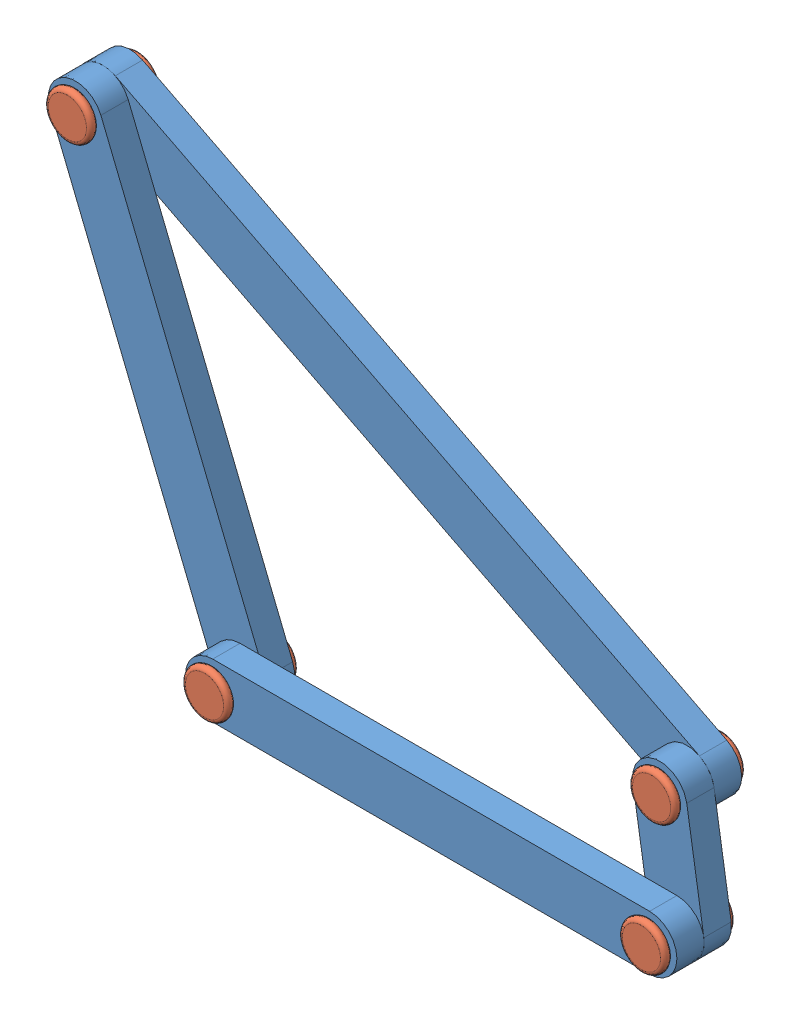
SolidWorks assembly four_bar_linkage, configuration Default. Lengths in mm.
Overall size (155.65 110.94 22.86).
8 component instances, 2 part files, 15 mates.
Components (placement in the parent):
- link-1: link [4] at (-72.1431 -68.9681 0) size (114.3 12.7 6.35)
- link_coupler-1: link_coupler [Default] at (-72.1431 -68.9681 -3.175) x (0 0 -1) z (0.970878 0.239573 0) size (16.51 10.79 10.79)
- link_coupler-2: link_coupler [Default] at (-173.7431 -68.9681 -3.175) x (0 0 -1) z (0.119211 -0.992869 0) size (16.51 10.79 10.79)
- link-2: link [4] at (-211.9868 25.1594 -6.35) x (-0.376415 0.926451 0) z (0 0 -1) size (114.3 12.7 6.35)
- link-3: link [1] at (-76.1226 -43.8817 -6.35) x (-0.156675 0.98765 0) z (0 0 1) size (38.1 12.7 6.35)
- link_coupler-3: link_coupler [Default] at (-211.9868 25.1594 -9.525) x (0 0 -1) z (0.614326 0.789053 0) size (16.51 10.79 10.79)
- link_coupler-4: link_coupler [Default] at (-76.1226 -43.8817 -9.525) x (0 0 -1) z (-0.985541 -0.16944 0) size (16.51 10.79 10.79)
- link-4: link [6] at (-76.1226 -43.8817 -12.7) x (0.891497 -0.453026 0) z (0 0 1) size (165.1 12.7 6.35)
Mates (geometry in assembly coordinates):
- Concentric1: concentric aligned: cylinder of link-1 through (-72.1431 -68.9681 3.175) axis (0 0 1) radius 3.175; cylinder of link_coupler-1 through (-72.1431 -68.9681 36.0678) axis (0 0 1) radius 3.175
- Coincident1: coincident anti-aligned: plane of link-1 through (-173.7431 -68.9681 3.175) normal (0 0 1); plane of link_coupler-1 through (-73.208 -64.6525 3.175) normal (0 0 -1)
- Concentric2: concentric aligned: cylinder of link-1 through (-173.7431 -68.9681 3.175) axis (0 0 1) radius 3.175; cylinder of link_coupler-2 through (-173.7431 -68.9681 36.0678) axis (0 0 1) radius 3.175
- Coincident2: coincident anti-aligned: plane of link-1 through (-173.7431 -68.9681 3.175) normal (0 0 1); plane of link_coupler-2 through (-169.3298 -68.4382 3.175) normal (0 0 -1)
- Concentric3: concentric anti-aligned: cylinder of link_coupler-2 through (-173.7431 -68.9681 36.0678) axis (0 0 1) radius 3.175; cylinder of link-2 through (-173.7431 -68.9681 -9.525) axis (0 0 -1) radius 3.175
- Coincident3: coincident anti-aligned: plane of link_coupler-2 through (-169.3298 -68.4382 -9.525) normal (0 0 1); plane of link-2 through (-173.7431 -68.9681 -9.525) normal (0 0 -1)
- Concentric4: concentric anti-aligned: cylinder of link-1 through (-72.1431 -68.9681 3.175) axis (0 0 -1) radius 6.35; cylinder of link-3 through (-72.1431 -68.9681 -3.175) axis (0 0 1) radius 3.175
- Coincident4: coincident anti-aligned: plane of link-1 through (-173.7431 -68.9681 -3.175) normal (0 0 -1); plane of link-3 through (-72.1431 -68.9681 -3.175) normal (0 0 1)
- Concentric5: concentric anti-aligned: cylinder of link-2 through (-211.9868 25.1594 -9.525) axis (0 0 -1) radius 3.175; cylinder of link_coupler-3 through (-211.9868 25.1594 29.7178) axis (0 0 1) radius 3.175
- Coincident5: coincident anti-aligned: plane of link-2 through (-173.7431 -68.9681 -3.175) normal (0 0 1); plane of link_coupler-3 through (-215.4942 27.8901 -3.175) normal (0 0 -1)
- Concentric6: concentric aligned: cylinder of link-3 through (-76.1226 -43.8817 -3.175) axis (0 0 1) radius 3.175; cylinder of link_coupler-4 through (-76.1226 -43.8817 29.7178) axis (0 0 1) radius 3.175
- Coincident6: coincident anti-aligned: plane of link-3 through (-72.1431 -68.9681 -3.175) normal (0 0 1); plane of link_coupler-4 through (-75.3695 -48.2625 -3.175) normal (0 0 -1)
- Concentric7: concentric aligned: cylinder of link-2 through (-211.9868 25.1594 -9.525) axis (0 0 1) radius 6.35; cylinder of link-4 through (-211.9868 25.1594 -9.525) axis (0 0 1) radius 3.175
- Coincident7: coincident anti-aligned: plane of link-2 through (-173.7431 -68.9681 -9.525) normal (0 0 -1); plane of link-4 through (-211.9868 25.1594 -9.525) normal (0 0 1)
- Coincident8: coincident aligned: cylinder of link_coupler-4 through (-76.1226 -43.8817 29.7178) axis (0 0 1) radius 3.175; circle of link-4
